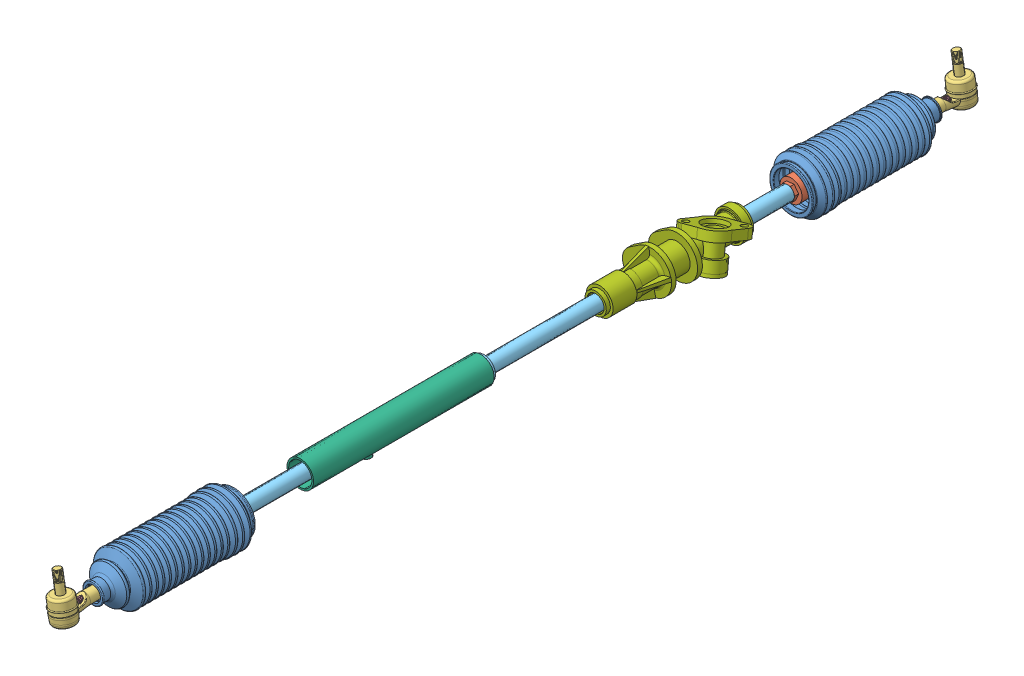
SolidWorks assembly Tie_rod_components, configuration Default. Lengths in mm.
Overall size (122.58 122.58 1505.65).
11 component instances, 7 part files, 20 mates.
Components (placement in the parent):
- CAO SU CHẤN BỤI-1: CAO SU CHẤN BỤI [Default] at (0 0 -6) x (0 0 -1) z (-0.625391 -0.780312 0) size (230.52 87.2 87.2)
- KHỚP CẦU 3-1: KHỚP CẦU 3 [Default] at (0 0 -6) x (0 0 1) z (0.77018 0.637826 0) size (48.52 36 36)
- ROTUYN NGOÀI-1: ROTUYN NGOÀI [Default] at (-1.0596 6.5722 -284.998) x (0 0 1) z (-0.987251 -0.159169 0) size (90.98 73 54.28)
- ROTUYN TRONG-1: ROTUYN TRONG [Default] at (0 0 904.1535) x (0 0 1) z (0.659009 -0.752135 0) size (257.66 24 24)
- THANH RĂNG-1: THANH RĂNG [Default] at origin size (38 38 898)
- THƯỚC LÁI-1: THƯỚC LÁI [Default] at (0 0 795.68) x (0 0 -1) z (-0.994491 -0.104823 0) size (295 48.35 43.5)
- CAO SU CHẤN BỤI-2: CAO SU CHẤN BỤI [Default] at (0 0 904) x (0 0 1) z (-0.923728 -0.383049 0) size (230.52 87.2 87.2)
- KHỚP CẦU 3-2: KHỚP CẦU 3 [Default] at (0 0 904) x (0 0 -1) z (0.656573 0.754262 0) size (48.52 36 36)
- ROTUYN NGOÀI-2: ROTUYN NGOÀI [Default] at (-1.1208 6.5621 1183.1535) x (0 0 -1) z (0.985724 0.168368 0) size (90.98 73 54.28)
- ROTUYN TRONG-2: ROTUYN TRONG [Default] at (0 0 -5.998) x (0 0 -1) z (0.453288 0.891364 0) size (257.66 24 24)
- VỎ CƠ CẤU LÁI-1: VỎ CƠ CẤU LÁI [Default] at (0 0 313.2225) x (0 0 -1) z (0.986691 0.162604 0) size (236.3 72.67 100.51)
Mates (geometry in assembly coordinates):
- Coincident1: coordinate: point of THANH RĂNG-1
- Concentric1: concentric anti-aligned: cylinder of KHỚP CẦU 3-1 through (0 0 -6.1535) axis (0 0 -1) radius 18; circle of THANH RĂNG-1
- Concentric2: concentric anti-aligned: cylinder of THANH RĂNG-1 through (0 0 598) axis (0 0 -1) radius 11.5; cylinder of KHỚP CẦU 3-2 through (0 0 904.1535) axis (0 0 1) radius 18
- Concentric4: concentric anti-aligned: cylinder of THANH RĂNG-1 through (0 0 598) axis (0 0 -1) radius 11.5; cylinder of ROTUYN TRONG-2 through (0 0 -16.998) axis (0 0 1) radius 6.5
- Coincident14: coincident anti-aligned: plane of KHỚP CẦU 3-1 through (0 0 0) normal (0 0 1); plane of THANH RĂNG-1 through (0 0 0) normal (0 0 -1)
- Coincident15: coincident aligned: cone of KHỚP CẦU 3-1 through (0 0 -31) axis (0 0 1); circle of ROTUYN TRONG-2
- Concentric12: concentric aligned: cylinder of ROTUYN NGOÀI-1 through (0 0 -249.748) axis (0 0 1) radius 9.5; cylinder of ROTUYN TRONG-2 through (0 0 -16.998) axis (0 0 1) radius 6.5
- Coincident16: coincident aligned: plane of ROTUYN NGOÀI-1 through (-8.1385 -9.9219 -212.998) normal (0 0 1); circle of ROTUYN TRONG-2
- Coincident17: coincident anti-aligned: circle of THANH RĂNG-1; plane of KHỚP CẦU 3-2 through (0 0 898) normal (0 0 -1)
- Concentric15: concentric aligned: cone of ROTUYN TRONG-1 through (0 0 930.3442) axis (0 0 -1); cone of KHỚP CẦU 3-2 through (0 0 929) axis (0 0 -1)
- Concentric16: concentric aligned: cylinder of ROTUYN TRONG-1 through (0 0 915.1535) axis (0 0 -1) radius 6.5; cylinder of ROTUYN NGOÀI-2 through (0 0 1147.9035) axis (0 0 -1) radius 9.5
- Coincident18: coincident aligned: circle of ROTUYN TRONG-1; plane of ROTUYN NGOÀI-2 through (10.9079 -6.76 1111.1535) normal (0 0 -1)
- Coincident19: coincident anti-aligned: plane of ROTUYN TRONG-1 through (0 0 904.1535) normal (0 0 -1); circle of KHỚP CẦU 3-2
- Concentric18: concentric aligned: circle of CAO SU CHẤN BỤI-1; cylinder of ROTUYN TRONG-2 through (0 0 -16.998) axis (0 0 1) radius 6.5
- Coincident20: coincident aligned: plane of CAO SU CHẤN BỤI-1 through (26.6944 -21.3946 -6) normal (0 0 1); plane of KHỚP CẦU 3-1 through (11.4809 -13.8632 -6) normal (0 0 1)
- Concentric19: concentric anti-aligned: cylinder of THANH RĂNG-1 through (0 0 598) axis (0 0 -1) radius 11.5; cylinder of THƯỚC LÁI-1 through (0 0 500.68) axis (0 0 1) radius 21.75
- Coincident21: coincident anti-aligned: plane of THANH RĂNG-1 through (0 0 500.68) normal (0 0 1); plane of THƯỚC LÁI-1 through (0 0 500.68) normal (0 0 -1)
- Concentric20: concentric aligned: cylinder of ROTUYN TRONG-1 through (0 0 915.1535) axis (0 0 -1) radius 6.5; circle of CAO SU CHẤN BỤI-2
- Coincident22: coincident aligned: plane of CAO SU CHẤN BỤI-2 through (-13.1041 31.6007 904) normal (0 0 -1); plane of KHỚP CẦU 3-2 through (-13.5767 11.8183 904) normal (0 0 -1)
- Concentric21: concentric anti-aligned: cylinder of THANH RĂNG-1 through (0 0 598) axis (0 0 -1) radius 11.5; cylinder of VỎ CƠ CẤU LÁI-1 through (0 0 313.2225) axis (0 0 1) radius 21.75
